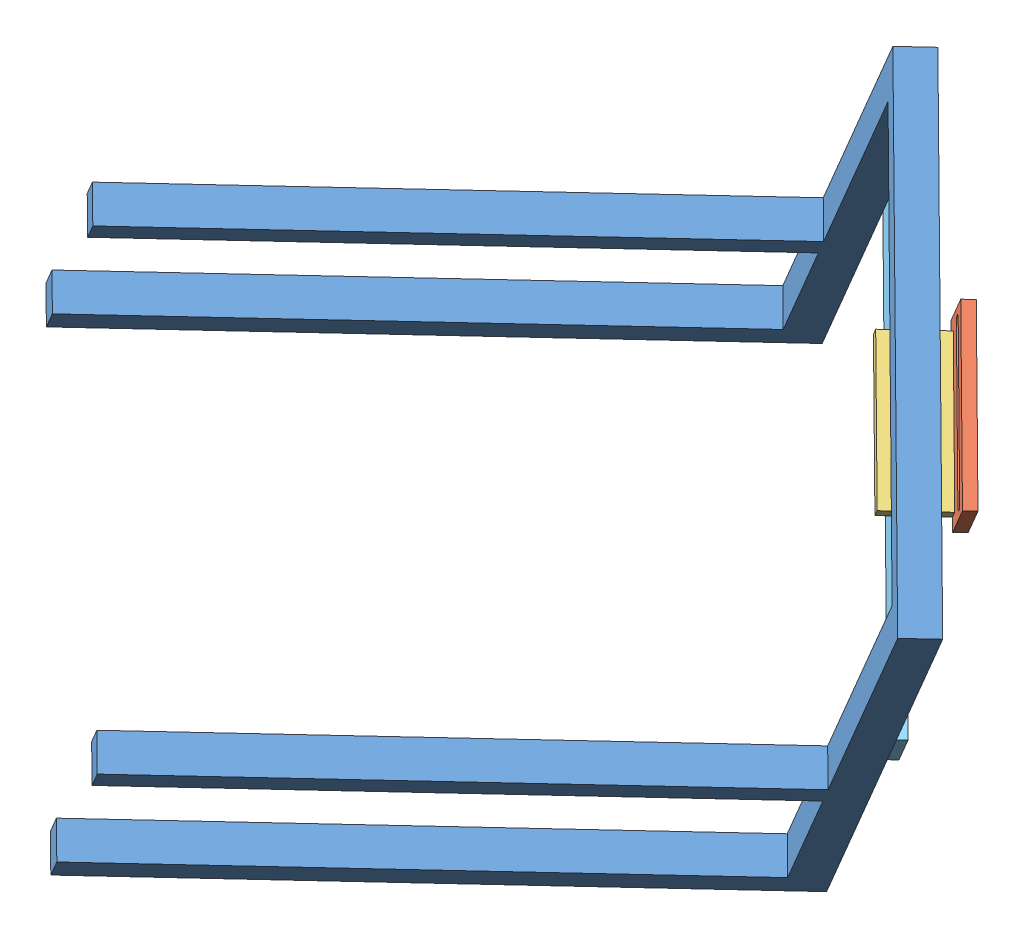
SolidWorks assembly Ensamblaje de la Base del Dosificador, configuration Predeterminado. Lengths in mm.
Overall size (1763.94 1570.11 1658.42).
5 component instances, 5 part files, 11 mates.
Components (placement in the parent):
- Dibujo de Mesa-1: Dibujo de Mesa [Predeterminado] at (-534.9205 -7.3317 50.7753) x (-0.534355 -0.759074 -0.371849) z (-0.545436 0.645728 -0.534355) size (1293.4 1000 783)
- Pieza2-1: Pieza2 [Predeterminado] at (-520.3606 -6.0821 -35.2058) x (0.545436 -0.645728 0.534355) z (0.534355 0.759074 0.371849) size (280 20 110)
- Pieza3-1: Pieza3 [Predeterminado] at (-537.6971 -51.015 -45.0573) x (0.545436 -0.645728 0.534355) z (0.534355 0.759074 0.371849) size (240 100 25)
- Pieza6-1: Pieza6 [Predeterminado] at (-564.2969 -63.4361 -7.6228) x (0.545436 -0.645728 0.534355) z (-0.645728 0.082715 0.759074) size (240 50 30)
- Pieza8-1: Pieza8 [Predeterminado] at (-811.9854 88.2884 -215.0985) x (0.545436 -0.645728 0.534355) z (0.534355 0.759074 0.371849) size (785 15 102)
Mates (geometry in assembly coordinates):
- Coincidente3: coincident aligned: plane of Pieza2-1 through (-606.3386 30.3527 -138.6637) normal (-0.534355 -0.759074 -0.371849); plane of Pieza3-1 through (-672.9173 27.364 -36.8877) normal (-0.534355 -0.759074 -0.371849)
- Coincidente4: coincident anti-aligned: plane of Pieza2-1 through (-520.3606 -6.0821 -35.2058) normal (-0.645728 0.082715 0.759074); plane of Pieza3-1 through (-537.6971 -51.015 -45.0573) normal (0.645728 -0.082715 -0.759074)
- Coincidente5: coincident anti-aligned: plane of Pieza3-1 through (-672.9173 27.364 -36.8877) normal (-0.534355 -0.759074 -0.371849); plane of Pieza6-1 through (-564.2969 -63.4361 -7.6228) normal (0.534355 0.759074 0.371849)
- Distancia1: distance = 40.4356 mm aligned: plane of Pieza6-1 through (-666.1528 -22.6617 -78.9517) normal (-0.645728 0.082715 0.759074); plane of Pieza3-1 through (-602.2699 -42.7435 30.8501) normal (-0.645728 0.082715 0.759074)
- Coincidente12: coincident anti-aligned: plane of Pieza3-1 through (-672.9173 27.364 -36.8877) normal (-0.534355 -0.759074 -0.371849); plane of Pieza8-1 through (-792.2979 186.0364 -189.2412) normal (0.534355 0.759074 0.371849)
- Coincidente13: coincident anti-aligned: plane of Pieza6-1 through (-666.1528 -22.6617 -78.9517) normal (-0.645728 0.082715 0.759074); plane of Pieza8-1 through (-811.9854 88.2884 -215.0985) normal (0.645728 -0.082715 -0.759074)
- Coincidente23: coincident aligned: plane of Dibujo de Mesa-1 through (-126.3903 74.8605 465.7557) normal (0.545436 -0.645728 0.534355); plane of Pieza8-1 through (-418.635 -398.2857 192.2987) normal (0.545436 -0.645728 0.534355)
- Distancia2: distance = 515 mm aligned: plane of Pieza8-1 through (-792.2979 186.0364 -189.2412) normal (0.534355 0.759074 0.371849); plane of Dibujo de Mesa-1 through (-126.3903 74.8605 465.7557) normal (0.534355 0.759074 0.371849)
- Concéntrica1: concentric anti-aligned: cylinder of Pieza6-1 through (-614.3319 -28.7668 -73.7252) axis (-0.645728 0.082715 0.759074) radius 4.7675; cylinder of Pieza8-1 through (-643.3896 -25.0446 -39.5669) axis (0.645728 -0.082715 -0.759074) radius 5
- Concéntrica2: concentric anti-aligned: cylinder of Pieza2-1 through (-550.57 -18.2744 -85.9236) axis (-0.645728 0.082715 0.759074) radius 5; cylinder of Pieza3-1 through (-579.6277 -14.5522 -51.7653) axis (0.645728 -0.082715 -0.759074) radius 4.25
- Coincidente24: coincident anti-aligned: plane of Dibujo de Mesa-1 through (-534.9205 -7.3317 50.7753) normal (0.645728 -0.082715 -0.759074); plane of Pieza8-1 through (-821.6714 89.5291 -203.7123) normal (-0.645728 0.082715 0.759074)
